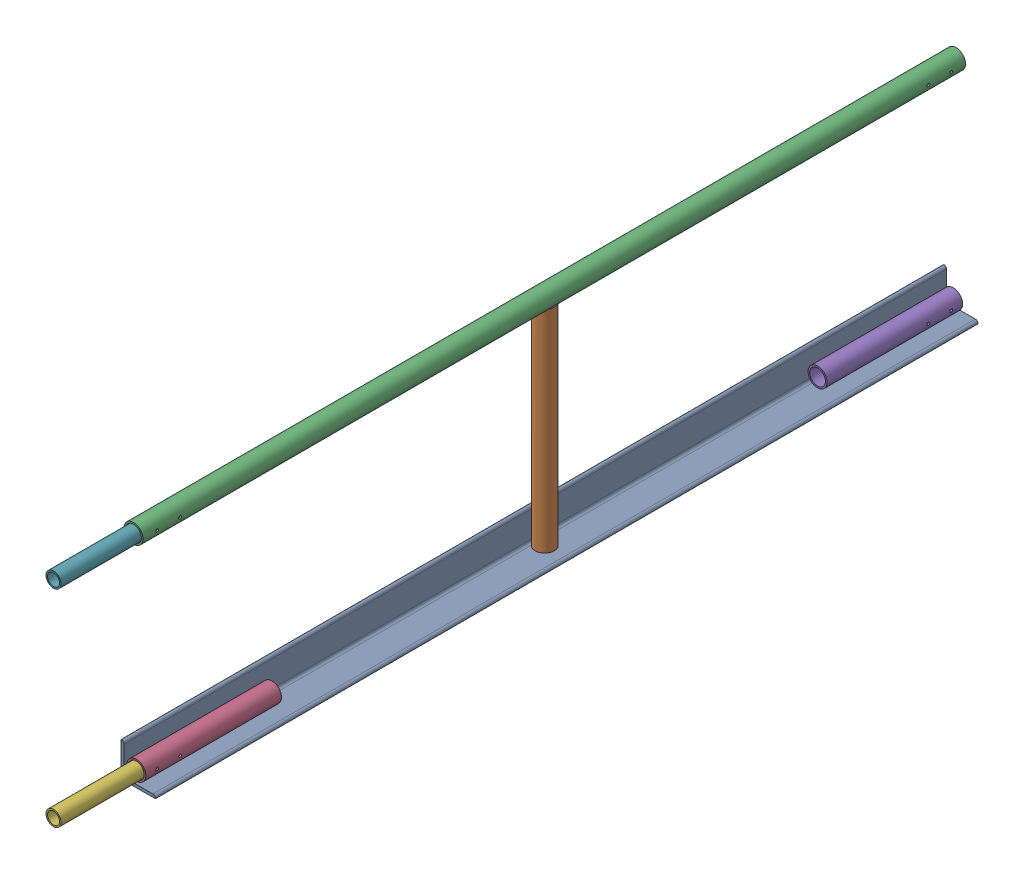
SolidWorks assembly FE-00022_ASM, configuration Default. Lengths in mm.
Overall size (76.2 507.65 2006.6).
8 component instances, 5 part files, 0 mates.
Components (placement in the parent):
- FE-00005_ASM-1: FE-00005_ASM [Default] at origin size (76.2 507.65 1828.8)
  - FE-00005-01-1: FE-00005-01 [Default] at origin size (76.2 76.2 1828.8)
  - FE-00005-03-1: FE-00005-03 [Default] at (27.432 6.35 914.4) size (42.16 471.23 42.16)
  - FE-00005-04-1: FE-00005-04 [Default] at (27.432 486.5688 0) size (42.16 42.16 1828.8)
  - FE-00005-02-1: FE-00005-02 [Default] at (27.432 27.432 1520.825) size (42.16 42.16 301.62)
  - FE-00005-02-2: FE-00005-02 [Default] at (27.432 27.432 307.975) x (1 0 0) z (0 0 -1) size (42.16 42.16 301.62)
- FE-00026-1: FE-00026 [Default] at (27.432 27.432 1651) size (33.4 33.4 355.6)
- FE-00026-2: FE-00026 [Default] at (27.432 486.5688 1651) x (-1 0 0) z (0 0 1) size (33.4 33.4 355.6)
